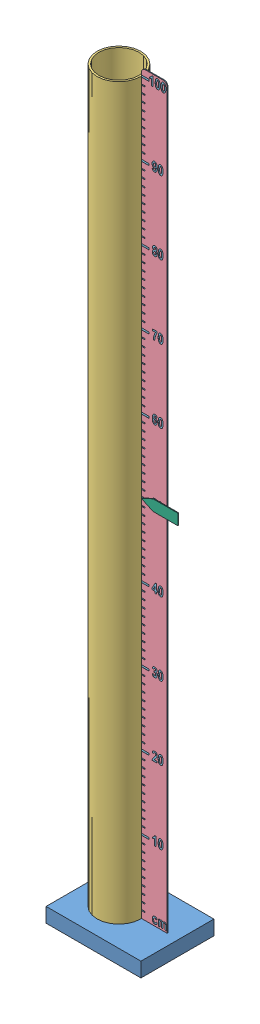
SolidWorks assembly montagem, configuration Valor predeterminado. Lengths in mm.
Overall size (131.16 1030 100).
6 component instances, 6 part files, 12 mates.
Components (placement in the parent):
- base-1: base [Valor predeterminado] at (0 -100 0) size (130 20 100)
- esfera-1: esfera [Valor predeterminado] at (0 -64.8266 0) x (0.679095 0.729921 -0.077755) z (-0.7337 0.678227 -0.04114) size (50 50 50)
- tubo-1: tubo [Valor predeterminado] at (0 -30 0) size (60 1000 60)
- regua-1: regua [Valor predeterminado] at (30 -90 -1.1317) size (35 1010 0.1)
- fundo_regua-1: fundo_regua [Valor predeterminado] at (30 -90 -2.1317) size (35 1010 1)
- indicador-1: indicador [Valor predeterminado] at (31.3547 409.9882 -0.5317) size (50 15 1)
Mates (geometry in assembly coordinates):
- Concêntrico1: concentric: sphere of esfera-1; cylinder of tubo-1 through (0 -90 0) axis (0 1 0) radius 27.5
- Coincidente1: coincident anti-aligned: plane of base-1 through (0 -90 0) normal (0 1 0); plane of tubo-1 through (0 -90 0) normal (0 -1 0)
- Coincidente11: coincident aligned: plane of base-1 through (0 -100 0) normal (0 0 1); plane of assembly through (0 0 0) normal (0 0 1)
- Coincidente12: coincident aligned: plane of base-1 through (0 -100 0) normal (1 0 0); plane of assembly through (0 0 0) normal (1 0 0)
- Distância2: distance = 100 mm aligned: plane of base-1 through (0 -100 0) normal (0 1 0); plane of assembly through (0 0 0) normal (0 1 0)
- Coincidente14: coincident aligned: plane of tubo-1 through (0 -30 0) normal (0 0 1); plane of assembly through (0 0 0) normal (0 0 1)
- Coincidente15: coincident aligned: plane of tubo-1 through (0 -30 0) normal (1 0 0); plane of assembly through (0 0 0) normal (1 0 0)
- Coincidente16: coincident anti-aligned: plane of base-1 through (0 -90 0) normal (0 1 0); plane of regua-1 through (30 -90 -1.0317) normal (0 -1 0)
- Tangente1: tangent anti-aligned: cylinder of tubo-1 through (0 -90 0) axis (0 1 0) radius 30; plane of regua-1 through (30 -90 -1.0317) normal (-1 0 0)
- Coincidente17: coincident anti-aligned: plane of base-1 through (0 -90 0) normal (0 1 0); plane of fundo_regua-1 through (30 -90 -1.1317) normal (0 -1 0)
- Coincidente18: coincident anti-aligned: plane of regua-1 through (30 -90 -1.1317) normal (0 0 -1); plane of fundo_regua-1 through (30 -90 -1.1317) normal (0 0 1)
- Tangente2: tangent anti-aligned: cylinder of tubo-1 through (0 -90 0) axis (0 1 0) radius 30; plane of fundo_regua-1 through (30 -90 -1.1317) normal (-1 0 0)
